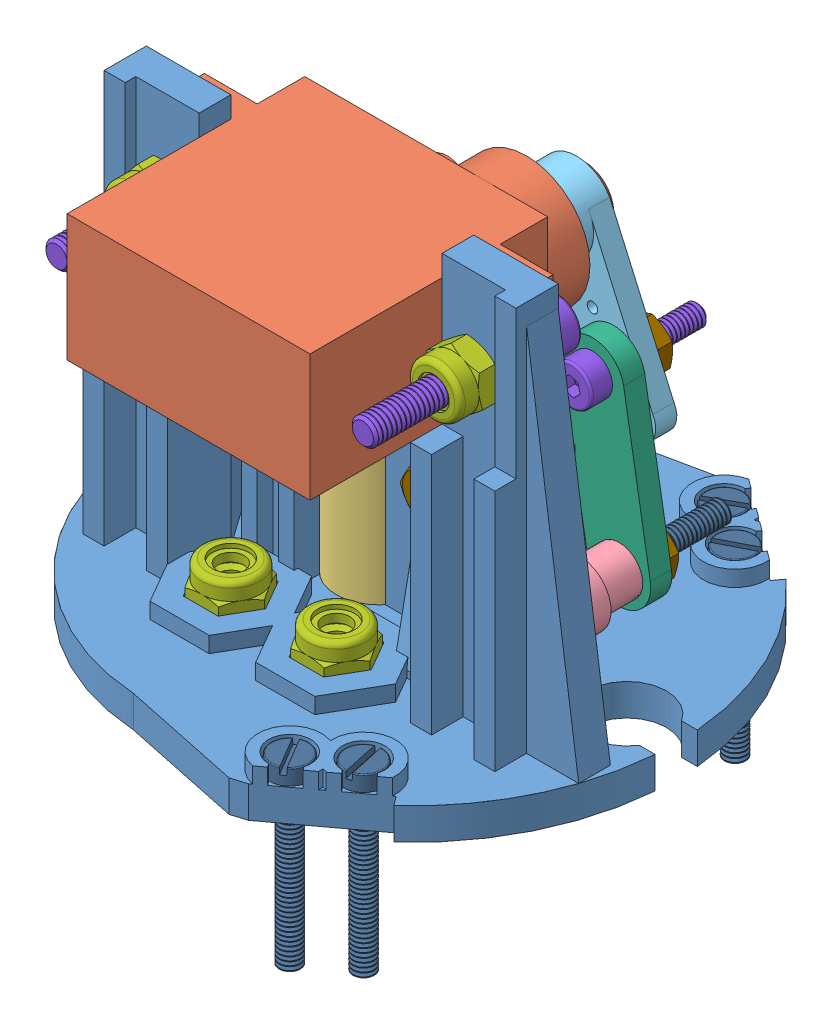
SolidWorks assembly Rückseite, configuration Standard. Lengths in mm.
Overall size (49.92 53 48.18).
27 component instances, 11 part files, 59 mates.
Components (placement in the parent):
- Backside-1: Backside [Standard] at (-0.7502 -6.4244 50) size (49.92 40 48.18)
- servo-1: servo [Standard] at (-9.7502 31.5756 70.5) x (1 0 0) z (0 1 0) size (33 29.25 12)
- Druecker-1: Druecker [Standard] at (-0.7502 19.306 50) x (1 0 0) z (0 0 -1) size (8 31.5 8)
- Hebel-1: Hebel [Standard] at (9.2498 10.5756 51) x (0.903963 -0.42761 0) z (0 0 -1) size (30.92 10.86 7.75)
- Servo-Arm-1: Servo-Arm [Standard] at (7.2498 25.5756 39.25) x (0.498599 -0.866833 0) z (-0.866833 -0.498599 0) size (20.6 4.3 7.2)
- Hebel2-1: Hebel2 [Standard] at (15.2611 1.2548 41.25) x (-0.168449 0.98571 0) z (0.98571 0.168449 0) size (21 2 6)
- User Library-Mutter DIN-985_-1: User Library-Mutter DIN-985_ [Mutter DIN-985 M3-A2] at (-4.7502 -3.4244 60) x (0 1 0) z (0 0 1) size (4 6.35 5.5)
- User Library-Mutter DIN-985_-2: User Library-Mutter DIN-985_ [Mutter DIN-985 M3-A2] at (5.2498 -3.4244 60) x (0 1 0) z (-0.866025 0 0.5) size (4 6.35 5.5)
- User Library-Mutter DIN-985_-3: User Library-Mutter DIN-985_ [Mutter DIN-985 M3-A2] at (5.2498 -3.4244 40) x (0 1 0) z (-0.866025 0 -0.5) size (4 6.35 5.5)
- User Library-Mutter DIN-985_-4: User Library-Mutter DIN-985_ [Mutter DIN-985 M3-A2] at (-4.7502 -3.4244 40) x (0 1 0) z (-0.866025 0 0.5) size (4 6.35 5.5)
- socket head cap screw 4762_din-1: socket head cap screw 4762_din [ISO 4762 M2 x 10 --- 10S] at (9.2498 10.5756 43.8) x (0 0 1) z (0.327477 -0.944859 0) size (12 3.8 3.8)
- socket head cap screw 4762_din-2: socket head cap screw 4762_din [ISO 4762 M2 x 10 --- 10S] at (-0.7502 15.306 55.5) x (0 0 -1) z (0.060223 0.998185 0) size (12 3.8 3.8)
- socket head cap screw 4762_din-3: socket head cap screw 4762_din [ISO 4762 M2 x 10 --- 10S] at (12.7344 16.0405 45.25) x (0 0 -1) z (-0.697004 0.717067 0) size (12 3.8 3.8)
- nut__style_1__m2x0_4__ansi_b18_2_4_1m-1: nut__style_1__m2x0_4__ansi_b18_2_4_1m [Default] at (-0.7502 15.306 46.5) x (0.866025 -0.5 0) z (0 0 -1) size (4.62 4 1.6)
- nut__style_1__m2x0_4__ansi_b18_2_4_1m-2: nut__style_1__m2x0_4__ansi_b18_2_4_1m [Default] at (12.7344 16.0405 37.65) x (-0.820318 0.571907 0) z (0 0 1) size (4.62 4 1.6)
- nut__style_1__m2x0_4__ansi_b18_2_4_1m-3: nut__style_1__m2x0_4__ansi_b18_2_4_1m [Default] at (9.2498 10.5756 54.2) x (0.532315 -0.846547 0) z (0 0 1) size (4.62 4 1.6)
- User Library-Mutter DIN-985_-5: User Library-Mutter DIN-985_ [Mutter DIN-985 M2,5-A2] at (-12.7502 25.5756 58) x (0 0 1) z (-0.937505 -0.347973 0) size (3.8 5.77 5)
- User Library-Mutter DIN-985_-6: User Library-Mutter DIN-985_ [Mutter DIN-985 M2,5-A2] at (16.2498 25.5756 58) x (0 0 1) z (-0.395566 -0.918438 0) size (3.8 5.77 5)
- slotted cheese head screw_din-1: slotted cheese head screw_din [ISO 1207 - M2 x 16 --- 16S] at (11.3929 -2.0244 70.5635) x (0 -1 0) z (0.511563 0 0.859246) size (17.41 3.8 3.8)
- slotted cheese head screw_din-2: slotted cheese head screw_din [ISO 1207 - M2 x 16 --- 16S] at (11.3929 -2.0244 29.4365) x (0 -1 0) z (-0.876101 0 0.482128) size (17.41 3.8 3.8)
- slotted cheese head screw_din-3: slotted cheese head screw_din [ISO 1207 - M2 x 16 --- 16S] at (15.4084 -2.0244 32.4156) x (0 -1 0) z (-0.890448 0 0.455085) size (17.41 3.8 3.8)
- slotted cheese head screw_din-4: slotted cheese head screw_din [ISO 1207 - M2 x 16 --- 16S] at (15.4084 -2.0244 67.5844) x (0 -1 0) z (0.212665 0 0.977125) size (17.41 3.8 3.8)
- slotted cheese head screw_din-5: slotted cheese head screw_din [ISO 1207 - M2 x 16 --- 16S] at (15.2611 1.2548 50.85) x (0 0 -1) z (0.575115 0.818073 0) size (17.41 3.8 3.8)
- nut__style_1__m2x0_4__ansi_b18_2_4_1m-4: nut__style_1__m2x0_4__ansi_b18_2_4_1m [Default] at (15.2611 1.2548 41.25) x (-0.746648 0.66522 0) z (0 0 -1) size (4.62 4 1.6)
- cross fh tapping 7976_din-2: cross fh tapping 7976_din [Tapping screw DIN 7982-ST2.9x6.5-C-Z-S] at (7.2498 25.5756 38.5) x (0 0 1) z (-0.95506 0.296413 0) size (6.51 5.5 5.5)
- socket head cap screw 4762_din-4: socket head cap screw 4762_din [ISO 4762 M2.5 x 16 --- 16S] at (-12.7502 25.5756 50) x (0 0 1) z (0.225641 0.974211 0) size (18.5 4.5 4.5)
- socket head cap screw 4762_din-5: socket head cap screw 4762_din [ISO 4762 M2.5 x 16 --- 16S] at (16.2498 25.5756 50) x (0 0 1) z (-0.799016 -0.60131 0) size (18.5 4.5 4.5)
Mates (geometry in assembly coordinates):
- Konzentrisch1: concentric anti-aligned: cylinder of Druecker-1 through (-0.7502 -12.3164 50) axis (0 1 0) radius 4; cylinder of Backside-1 through (-0.7502 -3.4244 50) axis (0 -1 0) radius 4
- Konzentrisch2: concentric aligned: cylinder of Backside-1 through (9.2498 10.5756 57.5) axis (0 0 1) radius 1.15; cylinder of Hebel-1 through (9.2498 10.5756 49) axis (0 0 1) radius 1.15
- Deckungsgleich1: coincident anti-aligned: plane of Hebel-1 through (9.2498 10.5756 49) normal (0 0 -1); plane of Backside-1 through (6.7498 13.5756 49) normal (0 0 1)
- Parallel1: parallel anti-aligned: plane of Druecker-1 through (-5.7502 11.1836 51) normal (0 0 -1); plane of Hebel-1 through (9.2498 10.5756 51) normal (0 0 1)
- Langloch1: slot anti-aligned: cylinder of ? through (-0.7502 15.1836 54) axis (0 0 -1) radius 1.1; cylinder of ? through (-5.2817 17.2716 49) axis (0 0 1) radius 1.15
- Konzentrisch3: concentric anti-aligned: cylinder of servo-1 through (7.2498 25.5756 44) axis (0 0 1) radius 6; cylinder of Servo-Arm-1 through (7.2498 25.5756 43.55) axis (0 0 -1) radius 2.25
- Deckungsgleich6: coincident anti-aligned: plane of Backside-1 through (-9.7502 31.5756 58) normal (1 0 0); plane of servo-1 through (-9.7502 31.5756 48) normal (-1 0 0)
- Deckungsgleich7: coincident anti-aligned: plane of servo-1 through (18.2498 31.5756 55) normal (0 0 1); plane of Backside-1 through (-17.7502 19.5756 55) normal (0 0 -1)
- Deckungsgleich9: coincident anti-aligned: plane of Hebel2-1 through (15.3545 1.3157 41.25) normal (0 0 -1); plane of Servo-Arm-1 through (7.2498 25.5756 41.25) normal (0 0 1)
- Konzentrisch4: concentric anti-aligned: cylinder of Hebel-1 through (15.3545 1.3157 47) axis (0 0 1) radius 1.15; cylinder of Hebel2-1 through (15.3545 1.3157 43.25) axis (0 0 -1) radius 1.15
- Deckungsgleich12: coincident anti-aligned: plane of servo-1 through (7.2498 25.5756 41.25) normal (0 0 -1); plane of Servo-Arm-1 through (7.2498 25.5756 41.25) normal (0 0 1)
- Konzentrisch5: concentric aligned: cylinder of Servo-Arm-1 through (12.8435 16.104 41.25) axis (0 0 -1) radius 0.5; cylinder of Hebel2-1 through (12.8435 16.104 43.25) axis (0 0 -1) radius 1.15
- Deckungsgleich28: coincident: plane of Backside-1 through (-0.7502 -3.4244 50) normal (0 1 0); plane of User Library-Mutter DIN-985_-1 through (-7.4789 -3.4244 60) normal (0 -1 0)
- Deckungsgleich29: coincident: plane of Backside-1 through (-0.7502 -3.4244 50) normal (0 1 0); plane of User Library-Mutter DIN-985_-2 through (3.8855 -3.4244 57.6369) normal (0 -1 0)
- Deckungsgleich31: coincident: plane of Backside-1 through (-0.7502 -3.4244 50) normal (0 1 0); plane of User Library-Mutter DIN-985_-3 through (6.6142 -3.4244 37.6369) normal (0 -1 0)
- Deckungsgleich30: coincident anti-aligned: plane of Backside-1 through (-0.7502 -3.4244 50) normal (0 1 0); plane of User Library-Mutter DIN-985_-4 through (-6.1145 -3.4244 37.6369) normal (0 -1 0)
- Deckungsgleich21: coincident anti-aligned: plane of Backside-1 through (9.2498 10.5756 45.8) normal (0 0 -1); plane of socket head cap screw 4762_din-1 through (7.351 10.5086 45.8) normal (0 0 1)
- Konzentrisch20: concentric anti-aligned: cylinder of Backside-1 through (9.2498 10.5756 57.5) axis (0 0 1) radius 1.15; cylinder of socket head cap screw 4762_din-1 through (9.2498 10.5756 12.05) axis (0 0 -1) radius 1
- Konzentrisch19: concentric anti-aligned: cylinder of Druecker-1 through (-0.7502 15.1836 54) axis (0 0 -1) radius 1.1; cylinder of socket head cap screw 4762_din-2 through (-0.7502 15.1836 87.25) axis (0 0 1) radius 1
- Deckungsgleich38: coincident anti-aligned: plane of Hebel2-1 through (15.3545 1.3157 43.25) normal (0 0 1); plane of socket head cap screw 4762_din-3 through (11.4627 14.7989 43.25) normal (0 0 -1)
- Konzentrisch38: concentric anti-aligned: cylinder of Hebel2-1 through (12.8435 16.104 43.25) axis (0 0 -1) radius 1.15; cylinder of socket head cap screw 4762_din-3 through (12.8435 16.104 77) axis (0 0 1) radius 1
- Deckungsgleich41: coincident anti-aligned: plane of Druecker-1 through (-0.7502 19.1836 46.5) normal (0 0 -1); plane of nut__style_1__m2x0_4__ansi_b18_2_4_1m-1 through (1.2503 14.0286 46.5) normal (0 0 1)
- Konzentrisch49: concentric aligned: circle of socket head cap screw 4762_din-2; circle of nut__style_1__m2x0_4__ansi_b18_2_4_1m-1
- Deckungsgleich39: coincident anti-aligned: plane of Servo-Arm-1 through (7.2498 25.5756 39.25) normal (0 0 -1); plane of nut__style_1__m2x0_4__ansi_b18_2_4_1m-2 through (15.109 15.6529 39.25) normal (0 0 1)
- Konzentrisch50: concentric anti-aligned: circle of socket head cap screw 4762_din-3; circle of nut__style_1__m2x0_4__ansi_b18_2_4_1m-2
- Deckungsgleich33: coincident anti-aligned: plane of Backside-1 through (9.2498 10.5756 54.2) normal (0 0 1); plane of nut__style_1__m2x0_4__ansi_b18_2_4_1m-3 through (10.4795 8.6201 54.2) normal (0 0 -1)
- Konzentrisch48: concentric aligned: circle of socket head cap screw 4762_din-1; circle of nut__style_1__m2x0_4__ansi_b18_2_4_1m-3
- Deckungsgleich36: coincident anti-aligned: plane of Backside-1 through (-11.7502 31.5756 58) normal (0 0 1); plane of User Library-Mutter DIN-985_-5 through (-12.1447 23.3307 58) normal (0 0 -1)
- Deckungsgleich37: coincident anti-aligned: plane of Backside-1 through (15.2498 31.5756 58) normal (0 0 1); plane of User Library-Mutter DIN-985_-6 through (14.1143 26.4954 58) normal (0 0 -1)
- Konzentrisch51: concentric aligned: circle of Backside-1; circle of User Library-Mutter DIN-985_-1
- Konzentrisch52: concentric aligned: circle of Backside-1; circle of User Library-Mutter DIN-985_-2
- Konzentrisch53: concentric: circle of Backside-1; circle of User Library-Mutter DIN-985_-4
- Konzentrisch54: concentric aligned: circle of Backside-1; circle of User Library-Mutter DIN-985_-3
- Konzentrisch55: concentric aligned: circle of User Library-Mutter DIN-985_-5; cylinder of Backside-1 through (-12.7502 25.5756 41) axis (0 0 1) radius 1.25
- Konzentrisch56: concentric aligned: circle of User Library-Mutter DIN-985_-6; cylinder of Backside-1 through (16.2498 25.5756 41) axis (0 0 1) radius 1.25
- Deckungsgleich40: coincident anti-aligned: plane of Druecker-1 through (-0.7502 15.1836 53.5) normal (0 0 1); plane of socket head cap screw 4762_din-2 through (-2.6467 15.298 53.5) normal (0 0 -1)
- Konzentrisch59: concentric: cylinder of Backside-1 through (15.4084 -13.4244 32.4156) axis (0 1 0) radius 1.1; cylinder of slotted cheese head screw_din-3 through (15.4084 30.7101 32.4156) axis (0 1 0) radius 1
- Konzentrisch60: concentric: cylinder of Backside-1 through (11.3929 -13.4244 29.4365) axis (0 1 0) radius 1.1; cylinder of slotted cheese head screw_din-2 through (11.3929 23.3756 29.4365) axis (0 1 0) radius 1
- Konzentrisch61: concentric: cylinder of Backside-1 through (15.4084 -13.4244 67.5844) axis (0 1 0) radius 1.1; cylinder of slotted cheese head screw_din-4 through (15.4084 29.1763 67.5844) axis (0 1 0) radius 1
- Konzentrisch62: concentric: cylinder of Backside-1 through (11.3929 -13.4244 70.5635) axis (0 1 0) radius 1.1; cylinder of slotted cheese head screw_din-1 through (11.3929 27.2099 70.5635) axis (0 1 0) radius 1
- Deckungsgleich42: coincident anti-aligned: plane of Backside-1 through (-0.7502 -3.4244 50) normal (0 1 0); plane of slotted cheese head screw_din-3 through (15.8635 -3.4244 33.306) normal (0 -1 0)
- Deckungsgleich43: coincident anti-aligned: plane of Backside-1 through (-0.7502 -3.4244 50) normal (0 1 0); plane of slotted cheese head screw_din-2 through (11.875 -3.4244 30.3126) normal (0 -1 0)
- Deckungsgleich44: coincident anti-aligned: plane of Backside-1 through (-0.7502 -3.4244 50) normal (0 1 0); plane of slotted cheese head screw_din-1 through (12.2521 -3.4244 70.052) normal (0 -1 0)
- Deckungsgleich45: coincident anti-aligned: plane of Backside-1 through (-0.7502 -3.4244 50) normal (0 1 0); plane of slotted cheese head screw_din-4 through (16.3856 -3.4244 67.3717) normal (0 -1 0)
- Konzentrisch64: concentric aligned: cylinder of Hebel-1 through (15.3545 1.3157 47) axis (0 0 1) radius 1.15; cylinder of slotted cheese head screw_din-5 through (15.3545 1.3157 76.25) axis (0 0 1) radius 1
- Deckungsgleich47: coincident aligned: circle of Hebel-1; plane of slotted cheese head screw_din-5 through (15.3545 2.3157 49.45) normal (0 0 -1)
- Deckungsgleich48: coincident anti-aligned: plane of Hebel2-1 through (15.3545 1.3157 41.25) normal (0 0 -1); plane of nut__style_1__m2x0_4__ansi_b18_2_4_1m-4 through (17.4899 0.4347 41.25) normal (0 0 1)
- Konzentrisch65: concentric anti-aligned: cylinder of Hebel2-1 through (15.3545 1.3157 43.25) axis (0 0 -1) radius 1.15; cylinder of nut__style_1__m2x0_4__ansi_b18_2_4_1m-4 through (15.3545 1.3157 41.25) axis (0 0 1) radius 0.7835
- Deckungsgleich50: coincident: circle of Servo-Arm-1; cone of cross fh tapping 7976_din-2 through (7.2498 25.5756 40.2) axis (0 0 1)
- Parallel2: parallel: plane of Backside-1 through (10.5481 -1.9244 43.4769) normal (-0.866025 0 0.5); plane of User Library-Mutter DIN-985_-3 through (8.4252 0.5766 40) normal (0.866025 0 -0.5)
- Parallel3: parallel: plane of Backside-1 through (3.0481 -1.9244 47.8071) normal (-0.866025 0 0.5); plane of User Library-Mutter DIN-985_-4 through (-1.5748 0.5766 40) normal (0.866025 0 -0.5)
- Parallel4: parallel: plane of Backside-1 through (3.0481 -1.9244 52.1929) normal (-0.866025 0 -0.5); plane of User Library-Mutter DIN-985_-1 through (-3.1625 0.5766 62.75) normal (0.866025 0 0.5)
- Parallel5: parallel: plane of Backside-1 through (10.5481 -1.9244 56.5231) normal (-0.866025 0 -0.5); plane of User Library-Mutter DIN-985_-2 through (6.8375 0.5766 62.75) normal (0.866025 0 0.5)
- Parallel6: parallel anti-aligned: plane of Druecker-1 through (-2.8002 16.3671 46.5) normal (0.5 -0.866025 0); plane of nut__style_1__m2x0_4__ansi_b18_2_4_1m-1 through (-2.7507 16.3386 44.9) normal (-0.5 0.866025 0)
- Deckungsgleich51: coincident anti-aligned: plane of Backside-1 through (-0.7502 19.5756 50) normal (0 1 0); plane of servo-1 through (-9.7502 19.5756 48) normal (0 -1 0)
- Konzentrisch66: concentric anti-aligned: circle of socket head cap screw 4762_din-4; circle of User Library-Mutter DIN-985_-5
- Konzentrisch67: concentric anti-aligned: circle of socket head cap screw 4762_din-5; circle of User Library-Mutter DIN-985_-6
- Deckungsgleich52: coincident anti-aligned: plane of servo-1 through (18.2498 31.5756 52.5) normal (0 0 -1); plane of socket head cap screw 4762_din-5 through (14.8969 27.3734 52.5) normal (0 0 1)
- Deckungsgleich53: coincident anti-aligned: plane of servo-1 through (18.2498 31.5756 52.5) normal (0 0 -1); plane of socket head cap screw 4762_din-4 through (-10.5424 25.1417 52.5) normal (0 0 1)
